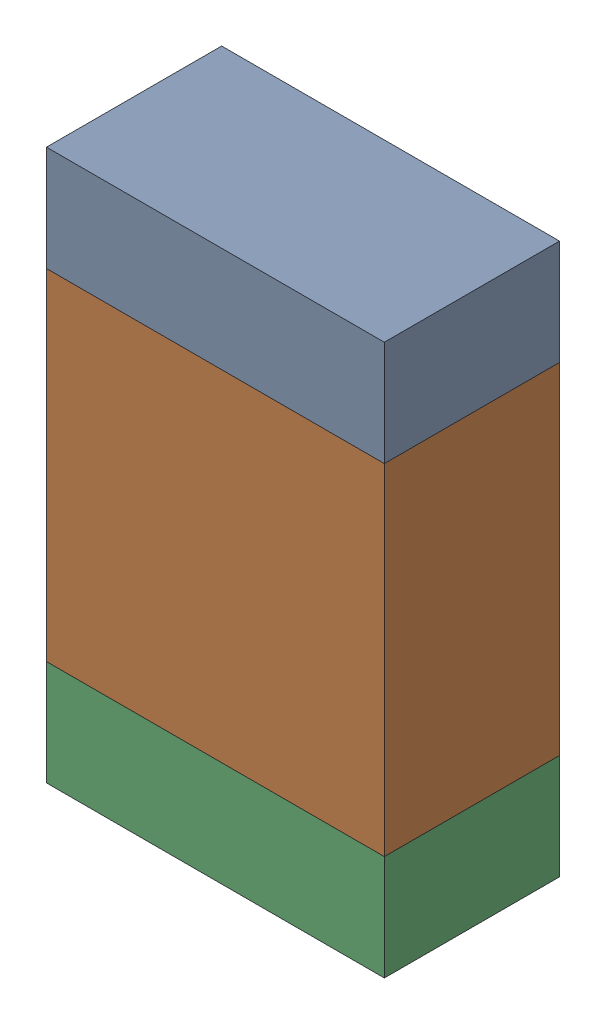
SolidWorks assembly R9, configuration Default. Lengths in mm.
Overall size (1.35 2.2 0.7).
6 component instances, 2 part files, 0 mates.
Components (placement in the parent):
- 959207304-1: 959207304 [Default] at (77.5971 95.5049 0) size (1.35 0.42 0.7)
  - Extruded-8-1: Extruded-8 [Default] at origin size (1.35 0.42 0.7)
- 959207440-1: 959207440 [Default] at (77.5971 94.6149 0) size (1.35 1.36 0.7)
  - Extruded-9-1: Extruded-9 [Default] at origin size (1.35 1.36 0.7)
- 959207304-2: 959207304 [Default] at (77.5971 93.7249 0) size (1.35 0.42 0.7)
  - Extruded-8-1: Extruded-8 [Default] at origin size (1.35 0.42 0.7)
